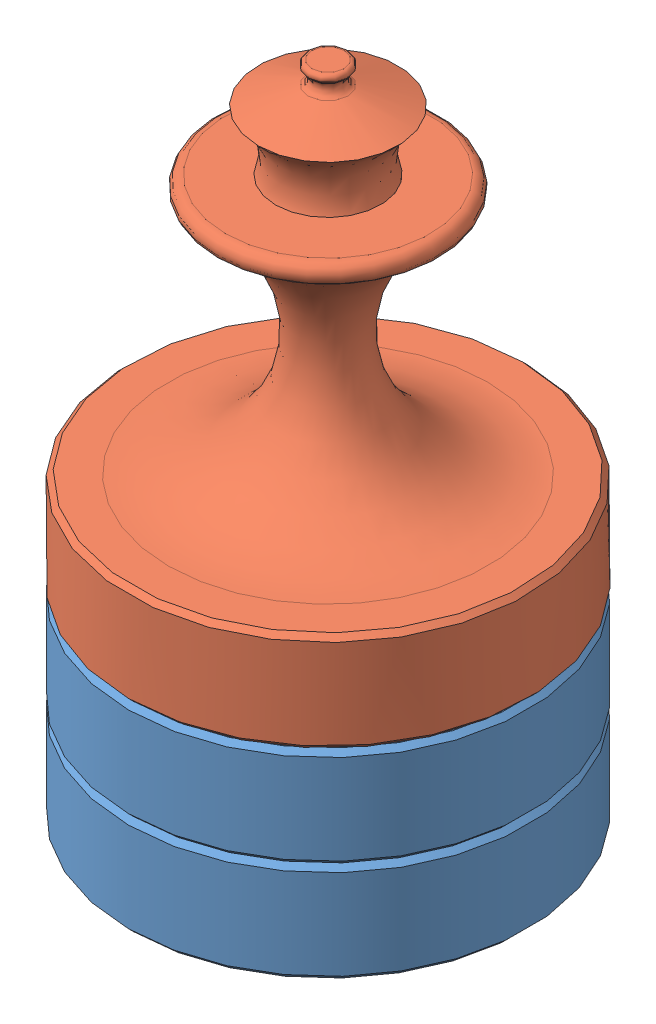
SolidWorks assembly Assemblage2, configuration Default. Lengths in mm.
Overall size (200 330 200).
3 component instances, 2 part files, 4 mates.
Components (placement in the parent):
- Pion-1: Pion [Default] at (12.2803 -6.2278 -19.2337) size (200 50 200)
- roi_reine-1: roi_reine [Default] at (12.2803 143.7722 -19.2337) size (200 230 200)
- Pion-2: Pion [Default] at (12.2803 43.7722 -19.2337) size (200 50 200)
Mates (geometry in assembly coordinates):
- Coïncidente1: coincident: plane of Pion-1 through (12.2803 43.7722 -19.2337) normal (0 1 0); plane of ? through (-37.9205 43.7722 -45.3013) normal (0 -1 0)
- Coaxiale1: concentric aligned: cylinder of Pion-1; cylinder of ?
- Coïncidente2: coincident: plane of ? through (-0.5049 93.7722 -137.5455) normal (0 -1 0); plane of Pion-2 through (12.2803 93.7722 -19.2337) normal (0 1 0)
- Coaxiale2: concentric anti-aligned: cylinder of ?; cylinder of Pion-2
